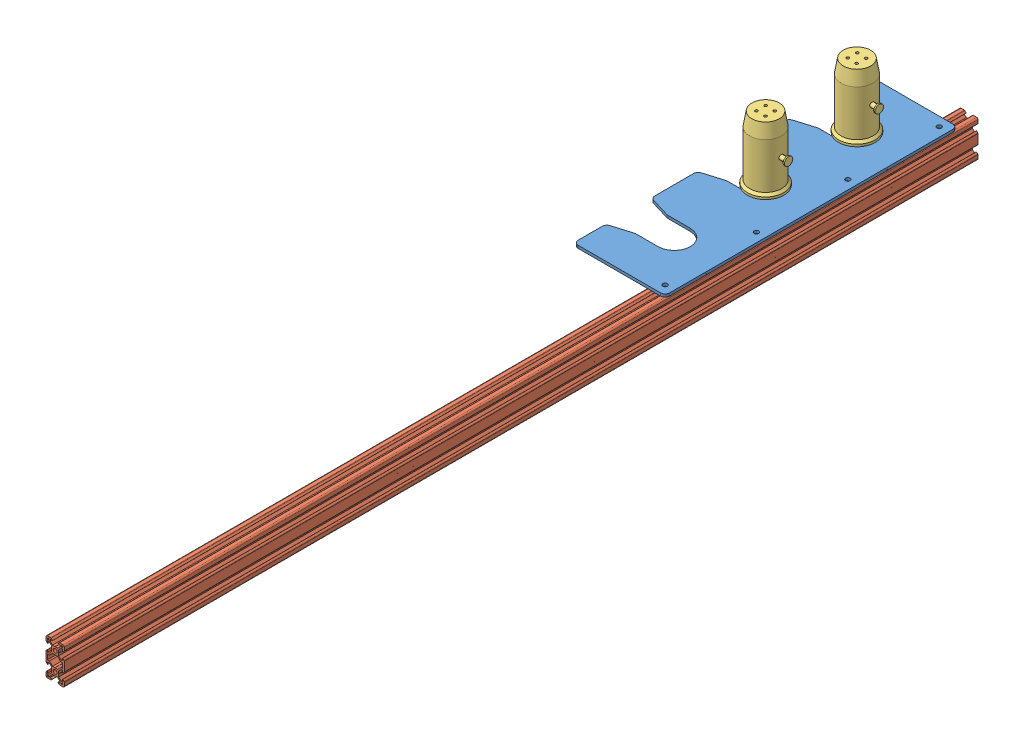
SolidWorks assembly Tool Holder Assembly, configuration Default. Lengths in mm.
Overall size (100 93 1000).
4 component instances, 3 part files, 7 mates.
Components (placement in the parent):
- Tool Holder-1: Tool Holder [Default] at (99.9771 110.4377 0) x (0 0 -1) z (1 0 0) size (320 3 100)
- V-Slot 20mm x 40mm-1: V-Slot 20mm x 40mm [1000mm] at (89.9771 100.4402 817.5263) size (20 40 1000)
- Tool Base-1: Tool Base [Default] at (49.9771 103.4377 -100) x (0.999165 0 0.040862) z (-0.040862 0 0.999165) size (41.5 60 40)
- Tool Base-2: Tool Base [Default] at (49.9771 103.4377 0) x (0.999946 0 0.010387) z (-0.010387 0 0.999946) size (41.5 60 40)
Mates (geometry in assembly coordinates):
- Coincident1: coincident anti-aligned: plane of Tool Holder-1 through (99.9771 110.4377 0) normal (0 -1 0); plane of V-Slot 20mm x 40mm-1 through (85.0699 110.4377 -182.4737) normal (0 1 0)
- Coincident2: coincident aligned: plane of Tool Holder-1 through (99.9771 113.4377 160) normal (1 0 0); plane of V-Slot 20mm x 40mm-1 through (99.9771 95.5288 -182.4737) normal (1 0 0)
- Coincident3: coincident anti-aligned: plane of Tool Holder-1 through (99.9771 110.4377 0) normal (0 0 -1); plane of assembly through (0 0 0) normal (0 0 1)
- Coincident4: coincident anti-aligned: plane of Tool Holder-1 through (99.9771 113.4377 0) normal (0 1 0); plane of Tool Base-2 through (49.9771 113.4377 0) normal (0 -1 0)
- Concentric1: concentric anti-aligned: cylinder of Tool Holder-1 through (49.9771 110.4377 -100) axis (0 1 0) radius 17.5; cylinder of Tool Base-1 through (49.9771 103.4377 -100) axis (0 -1 0) radius 17.5
- Concentric2: concentric anti-aligned: cylinder of Tool Holder-1 through (49.9771 110.4377 0) axis (0 1 0) radius 17.5; cylinder of Tool Base-2 through (49.9771 103.4377 0) axis (0 -1 0) radius 17.5
- Coincident5: coincident anti-aligned: plane of Tool Holder-1 through (99.9771 113.4377 0) normal (0 1 0); plane of Tool Base-1 through (49.9771 113.4377 -100) normal (0 -1 0)
